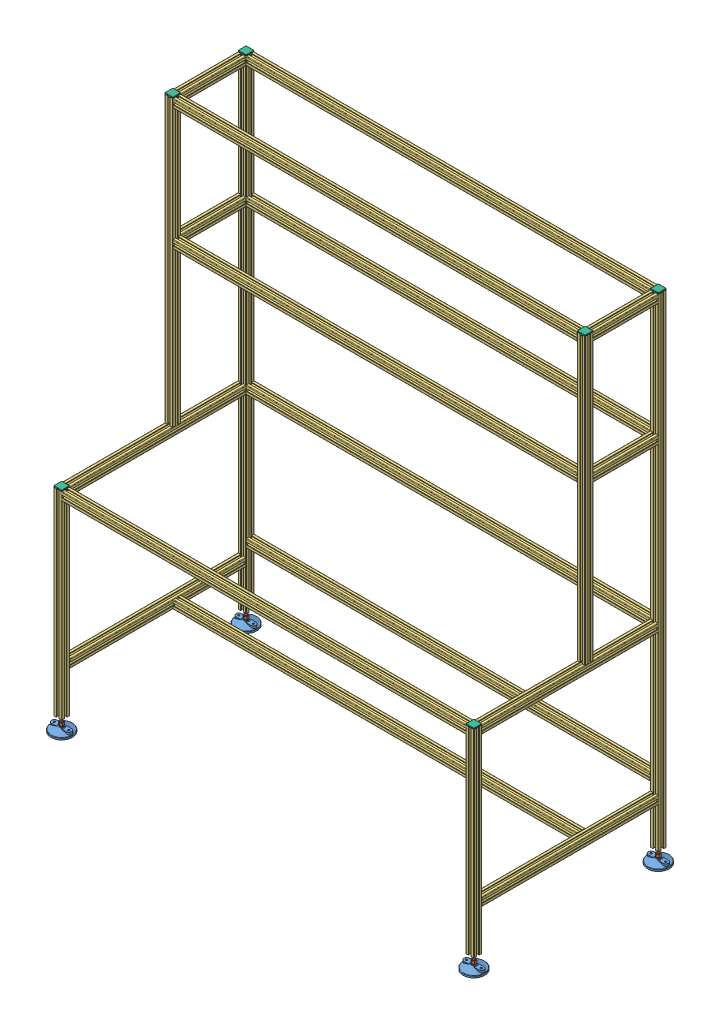
SolidWorks assembly AL-4 Рабочий стол большой с двумя полками, configuration По умолчанию. Lengths in mm.
Overall size (1599 1834.2 759).
75 component instances, 6 part files, 66 mates.
Components (placement in the parent):
- AL-340.010BA.01 Опора D80 с противоскользящей вставкой-8: AL-340.010BA.01 Опора D80 с противоскользящей вставкой [Default] x (0 0 1) z (1 0 0) size (79 18 79)
- AL-1Y12.A42A.01 Шпилька к опоре М8х80-1: AL-1Y12.A42A.01 Шпилька к опоре М8х80 [Default] x (0.999247 0 0.038788) z (0.038788 0 -0.999247) size (15 105.5 18.13)
- AL-4-PS-3030.001 Профиль-2: AL-4-PS-3030.001 Профиль [Default] at (0 1765 255) size (30 30 240)
- AL-4-PS-3030.001 Профиль-6: AL-4-PS-3030.001 Профиль [Default] at (-1520 1765 255) size (30 30 240)
- AL-4-PS-3030.001 Профиль-30: AL-4-PS-3030.001 Профиль [-01] at (0 715 665) x (0 1 0) z (0 0 1) size (30 30 650)
- AL-4-PS-3030.001 Профиль-31: AL-4-PS-3030.001 Профиль [-01] at (-1520 715 665) x (0 1 0) z (0 0 1) size (30 30 650)
- AL-4-PS-3030.001 Профиль-32: AL-4-PS-3030.001 Профиль [-01] at (0 165 665) size (30 30 650)
- AL-4-PS-3030.001 Профиль-33: AL-4-PS-3030.001 Профиль [-01] at (-1520 165 665) size (30 30 650)
- AL-4-PS-3030.001 Профиль-34: AL-4-PS-3030.001 Профиль [-02] at (0 0 680) x (1 0 0) z (0 -1 0) size (30 30 730)
- AL-4-PS-3030.001 Профиль-36: AL-4-PS-3030.001 Профиль [-03] at (0 730 270) x (0 0 1) z (0 -1 0) size (30 30 1050)
- AL-4-PS-3030.001 Профиль-35: AL-4-PS-3030.001 Профиль [-02] at (-1520 0 680) x (1 0 0) z (0 -1 0) size (30 30 730)
- AL-4-PS-3030.001 Профиль-38: AL-4-PS-3030.001 Профиль [-04] at (-1505 1765 270) x (0 0 1) z (-1 0 0) size (30 30 1490)
- AL-4-PS-3030.001 Профиль-40: AL-4-PS-3030.001 Профиль [-04] at (-1505 715 680) x (0 0 1) z (-1 0 0) size (30 30 1490)
- AL-4-PS-3030.001 Профиль-41: AL-4-PS-3030.001 Профиль [-04] at (-1505 715 0) x (0 0 1) z (-1 0 0) size (30 30 1490)
- AL-4-PS-3030.001 Профиль-42: AL-4-PS-3030.001 Профиль [-04] at (-1505 225 0) x (0 0 1) z (-1 0 0) size (30 30 1490)
- AL-4-PS-3030.001 Профиль-43: AL-4-PS-3030.001 Профиль [-04] at (-1505 1765 0) x (0 0 1) z (-1 0 0) size (30 30 1490)
- AL-4-PS-3030.001 Профиль-45: AL-4-PS-3030.001 Профиль [-04] at (-1505 165 270) x (0 0 1) z (-1 0 0) size (30 30 1490)
- AL-4-PS-3030.001 Профиль-46: AL-4-PS-3030.001 Профиль [-05] x (1 0 0) z (0 -1 0) size (30 30 1780)
- AL-4-PS-3030.001 Профиль-47: AL-4-PS-3030.001 Профиль [-05] at (-1520 0 0) x (1 0 0) z (0 -1 0) size (30 30 1780)
- AL-340.010BA.01 Опора D80 с противоскользящей вставкой-9: AL-340.010BA.01 Опора D80 с противоскользящей вставкой [Default] at (-1520 0 0) x (0 0 1) z (1 0 0) size (79 18 79)
- AL-340.010BA.01 Опора D80 с противоскользящей вставкой-10: AL-340.010BA.01 Опора D80 с противоскользящей вставкой [Default] at (0 0 680) x (0 0 1) z (1 0 0) size (79 18 79)
- AL-340.010BA.01 Опора D80 с противоскользящей вставкой-11: AL-340.010BA.01 Опора D80 с противоскользящей вставкой [Default] at (-1520 0 680) x (0 0 1) z (1 0 0) size (79 18 79)
- AL-1Y12.A42A.01 Шпилька к опоре М8х80-2: AL-1Y12.A42A.01 Шпилька к опоре М8х80 [Default] at (-1520 0 0) x (0.999247 0 0.038788) z (0.038788 0 -0.999247) size (15 105.5 18.13)
- AL-1Y12.A42A.01 Шпилька к опоре М8х80-3: AL-1Y12.A42A.01 Шпилька к опоре М8х80 [Default] at (0 0 680) x (0.999247 0 0.038788) z (0.038788 0 -0.999247) size (15 105.5 18.13)
- AL-1Y12.A42A.01 Шпилька к опоре М8х80-4: AL-1Y12.A42A.01 Шпилька к опоре М8х80 [Default] at (-1520 0 680) x (0.999247 0 0.038788) z (0.038788 0 -0.999247) size (15 105.5 18.13)
- AL-4-PS-3030.001 Профиль-37: AL-4-PS-3030.001 Профиль [-03] at (-1520 730 270) x (0 0 1) z (0 -1 0) size (30 30 1050)
- AL-4-PS-3030.001 Профиль-44: AL-4-PS-3030.001 Профиль [-04] at (-1505 1315 0) x (0 0 1) z (-1 0 0) size (30 30 1490)
- AL-4-PS-3030.001 Профиль-27: AL-4-PS-3030.001 Профиль [Default] at (-1520 1315 255) size (30 30 240)
- AL-4-PS-3030.001 Профиль-39: AL-4-PS-3030.001 Профиль [-04] at (-1505 1315 270) x (0 0 1) z (-1 0 0) size (30 30 1490)
- AL-4-PS-3030.001 Профиль-29: AL-4-PS-3030.001 Профиль [Default] at (0 1315 255) size (30 30 240)
- hex nut gradec_din-1: hex nut gradec_din [Hexagon Nut ISO 4034 - M8 - N] at (0 -7.9 0) x (0.999967 0 0.008076) z (0 -1 0) size (13 15.01 7.9)
- hex nut gradec_din-2: hex nut gradec_din [Hexagon Nut ISO 4034 - M8 - N] at (-1520 -7.9 0) x (0.999967 0 0.008076) z (0 -1 0) size (13 15.01 7.9)
- hex nut gradec_din-3: hex nut gradec_din [Hexagon Nut ISO 4034 - M8 - N] at (0 -7.9 680) x (0.999967 0 0.008076) z (0 -1 0) size (13 15.01 7.9)
- hex nut gradec_din-4: hex nut gradec_din [Hexagon Nut ISO 4034 - M8 - N] at (-1520 -7.9 680) x (0.999967 0 0.008076) z (0 -1 0) size (13 15.01 7.9)
- socket button head screw_iso2-1: socket button head screw_iso2 [ISO 7380 - M8 x 25 - 25S] at (0 165 8.4) x (0 0 1) z (-1 0 0) size (29.4 14 14)
- socket button head screw_iso2-2: socket button head screw_iso2 [ISO 7380 - M8 x 25 - 25S] at (-8.4 225 0) x (-1 0 0) z (0 -0.924225 -0.381849) size (29.4 14 14)
- socket button head screw_iso2-3: socket button head screw_iso2 [ISO 7380 - M8 x 25 - 25S] at (-8.4 715 0) x (-1 0 0) z (0 -0.924225 -0.381849) size (29.4 14 14)
- socket button head screw_iso2-4: socket button head screw_iso2 [ISO 7380 - M8 x 25 - 25S] at (0 715 8.4) x (0 0 1) z (-0.432301 -0.901729 0) size (29.4 14 14)
- socket button head screw_iso2-5: socket button head screw_iso2 [ISO 7380 - M8 x 25 - 25S] at (-8.4 165 270) x (-1 0 0) z (0 -0.924225 -0.381849) size (29.4 14 14)
- socket button head screw_iso2-6: socket button head screw_iso2 [ISO 7380 - M8 x 25 - 25S] at (0 165 671.6) x (0 0 -1) z (0.381849 -0.924225 0) size (29.4 14 14)
- socket button head screw_iso2-7: socket button head screw_iso2 [ISO 7380 - M8 x 25 - 25S] at (0 715 671.6) x (0 0 -1) z (0.923728 0.383049 0) size (29.4 14 14)
- socket button head screw_iso2-9: socket button head screw_iso2 [ISO 7380 - M8 x 25 - 25S] at (-8.4 715 680) x (-1 0 0) z (0 -0.11281 -0.993617) size (29.4 14 14)
- socket button head screw_iso2-10: socket button head screw_iso2 [ISO 7380 - M8 x 25 - 25S] at (0 723.4 270) x (0 1 0) z (-0.924225 0 -0.381849) size (29.4 14 14)
- socket button head screw_iso2-11: socket button head screw_iso2 [ISO 7380 - M8 x 25 - 25S] at (-8.4 1765 0) x (-1 0 0) z (0 0 -1) size (29.4 14 14)
- socket button head screw_iso2-12: socket button head screw_iso2 [ISO 7380 - M8 x 25 - 25S] at (0 1765 8.4) x (0 0 1) z (-1 0 0) size (29.4 14 14)
- socket button head screw_iso2-13: socket button head screw_iso2 [ISO 7380 - M8 x 25 - 25S] at (-8.4 1315 0) x (-1 0 0) z (0 0 -1) size (29.4 14 14)
- socket button head screw_iso2-14: socket button head screw_iso2 [ISO 7380 - M8 x 25 - 25S] at (0 1315 8.4) x (0 0 1) z (-1 0 0) size (29.4 14 14)
- socket button head screw_iso2-17: socket button head screw_iso2 [ISO 7380 - M8 x 25 - 25S] at (-8.4 1765 270) x (-1 0 0) z (0 0 -1) size (29.4 14 14)
- socket button head screw_iso2-18: socket button head screw_iso2 [ISO 7380 - M8 x 25 - 25S] at (0 1765 261.6) x (0 0 -1) z (1 0 0) size (29.4 14 14)
- socket button head screw_iso2-19: socket button head screw_iso2 [ISO 7380 - M8 x 25 - 25S] at (-8.4 1315 270) x (-1 0 0) z (0 0 -1) size (29.4 14 14)
- socket button head screw_iso2-20: socket button head screw_iso2 [ISO 7380 - M8 x 25 - 25S] at (0 1315 261.6) x (0 0 -1) z (1 0 0) size (29.4 14 14)
- hex nut gradec_din-5: hex nut gradec_din [Hexagon Nut ISO 4034 - M8 - N] at (-1520 0 0) x (-0.999967 0 0.008076) z (0 1 0) size (13 15.01 7.9)
- socket button head screw_iso2-21: socket button head screw_iso2 [ISO 7380 - M8 x 25 - 25S] at (-1520 1315 8.4) x (0 0 1) z (-1 0 0) size (29.4 14 14)
- socket button head screw_iso2-22: socket button head screw_iso2 [ISO 7380 - M8 x 25 - 25S] at (-1511.6 1315 0) size (29.4 14 14)
- socket button head screw_iso2-23: socket button head screw_iso2 [ISO 7380 - M8 x 25 - 25S] at (-1520 1765 8.4) x (0 0 1) z (-1 0 0) size (29.4 14 14)
- socket button head screw_iso2-24: socket button head screw_iso2 [ISO 7380 - M8 x 25 - 25S] at (-1511.6 1765 0) size (29.4 14 14)
- socket button head screw_iso2-25: socket button head screw_iso2 [ISO 7380 - M8 x 25 - 25S] at (-1520 723.4 270) x (0 1 0) z (-0.924225 0 0.381849) size (29.4 14 14)
- socket button head screw_iso2-26: socket button head screw_iso2 [ISO 7380 - M8 x 25 - 25S] at (-1511.6 715 680) x (1 0 0) z (0 0.11281 0.993617) size (29.4 14 14)
- socket button head screw_iso2-27: socket button head screw_iso2 [ISO 7380 - M8 x 25 - 25S] at (-1520 715 671.6) x (0 0 -1) z (0.923728 -0.383049 0) size (29.4 14 14)
- socket button head screw_iso2-28: socket button head screw_iso2 [ISO 7380 - M8 x 25 - 25S] at (-1520 165 671.6) x (0 0 -1) z (0.381849 0.924225 0) size (29.4 14 14)
- socket button head screw_iso2-29: socket button head screw_iso2 [ISO 7380 - M8 x 25 - 25S] at (-1511.6 165 270) x (1 0 0) z (0 0.924225 0.381849) size (29.4 14 14)
- socket button head screw_iso2-30: socket button head screw_iso2 [ISO 7380 - M8 x 25 - 25S] at (-1520 715 8.4) x (0 0 1) z (-0.432301 0.901729 0) size (29.4 14 14)
- socket button head screw_iso2-31: socket button head screw_iso2 [ISO 7380 - M8 x 25 - 25S] at (-1511.6 715 0) x (1 0 0) z (0 0.924225 0.381849) size (29.4 14 14)
- socket button head screw_iso2-32: socket button head screw_iso2 [ISO 7380 - M8 x 25 - 25S] at (-1511.6 225 0) x (1 0 0) z (0 0.924225 0.381849) size (29.4 14 14)
- socket button head screw_iso2-33: socket button head screw_iso2 [ISO 7380 - M8 x 25 - 25S] at (-1520 165 8.4) x (0 0 1) z (-1 0 0) size (29.4 14 14)
- socket button head screw_iso2-34: socket button head screw_iso2 [ISO 7380 - M8 x 25 - 25S] at (-1511.6 1765 270) size (29.4 14 14)
- socket button head screw_iso2-35: socket button head screw_iso2 [ISO 7380 - M8 x 25 - 25S] at (-1520 1765 261.6) x (0 0 -1) z (1 0 0) size (29.4 14 14)
- socket button head screw_iso2-36: socket button head screw_iso2 [ISO 7380 - M8 x 25 - 25S] at (-1511.6 1315 270) size (29.4 14 14)
- socket button head screw_iso2-37: socket button head screw_iso2 [ISO 7380 - M8 x 25 - 25S] at (-1520 1315 261.6) x (0 0 -1) z (1 0 0) size (29.4 14 14)
- AL-375.0200A.01 Заглушка торцевая 30х30-34: AL-375.0200A.01 Заглушка торцевая 30х30 [По умолчанию] at (-15 1784.2 -15) x (1 0 0) z (0 -1 0) size (30 30 9.2)
- AL-375.0200A.01 Заглушка торцевая 30х30-35: AL-375.0200A.01 Заглушка торцевая 30х30 [По умолчанию] at (-15 734.2 665) x (1 0 0) z (0 -1 0) size (30 30 9.2)
- AL-375.0200A.01 Заглушка торцевая 30х30-36: AL-375.0200A.01 Заглушка торцевая 30х30 [По умолчанию] at (15 1784.2 285) x (-1 0 0) z (0 -1 0) size (30 30 9.2)
- AL-375.0200A.01 Заглушка торцевая 30х30-37: AL-375.0200A.01 Заглушка торцевая 30х30 [По умолчанию] at (-1535 734.2 665) x (1 0 0) z (0 -1 0) size (30 30 9.2)
- AL-375.0200A.01 Заглушка торцевая 30х30-38: AL-375.0200A.01 Заглушка торцевая 30х30 [По умолчанию] at (-1505 1784.2 285) x (-1 0 0) z (0 -1 0) size (30 30 9.2)
- AL-375.0200A.01 Заглушка торцевая 30х30-39: AL-375.0200A.01 Заглушка торцевая 30х30 [По умолчанию] at (-1535 1784.2 -15) x (1 0 0) z (0 -1 0) size (30 30 9.2)
Mates (geometry in assembly coordinates):
- Совпадение1: coincident aligned: plane of AL-3-PS-3030.001 Профиль-22 through (0 0 0) normal (0 0 1)
- Совпадение2: coincident anti-aligned: plane of AL-3-PS-3030.001 Профиль-22 through (0 0 0) normal (0 -1 0)
- Совпадение3: coincident aligned: plane of AL-3-PS-3030.001 Профиль-22 through (0 0 0) normal (1 0 0)
- Совпадение4: coincident aligned: plane of AL-3-PS-3030.001 Профиль-22 through (15 1780 13) normal (1 0 0); plane of AL-3-PS-3030.001 Профиль-2 through (15 1778 15) normal (1 0 0)
- Совпадение5: coincident anti-aligned: plane of AL-3-PS-3030.001 Профиль-22 through (4.75 1780 15) normal (0 0 1); plane of AL-3-PS-3030.001 Профиль-2 through (-8.05 1752.4 15) normal (0 0 -1)
- Совпадение6: coincident aligned: plane of AL-3-PS-3030.001 Профиль-22 through (-8.05 1780 -12.6) normal (0 1 0); plane of AL-3-PS-3030.001 Профиль-2 through (-4.75 1780 15) normal (0 1 0)
- Совпадение7: coincident aligned: plane of AL-3-PS-3030.001 Профиль-22 through (15 1780 13) normal (1 0 0); plane of AL-3-PS-3030.001 Профиль-11 through (15 730 667) normal (1 0 0)
- Совпадение8: coincident aligned: plane of AL-3-PS-3030.001 Профиль-22 through (-8.05 0 -12.6) normal (0 -1 0); plane of AL-3-PS-3030.001 Профиль-11 through (-8.05 0 667.4) normal (0 -1 0)
- Совпадение11: coincident anti-aligned: plane of AL-3-PS-3030.001 Профиль-11 through (4.75 730 665) normal (0 0 -1); plane of AL-3-PS-3030.001 Профиль-7 through (12.6 706.95 665) normal (0 0 1)
- Совпадение12: coincident anti-aligned: plane of AL-3-PS-3030.001 Профиль-22 through (4.75 1780 15) normal (0 0 1); plane of AL-3-PS-3030.001 Профиль-7 through (12.6 706.95 15) normal (0 0 -1)
- Расстояние1: distance = 150 mm aligned: plane of AL-3-PS-3030.001 Профиль-9 through (4.75 150 15) normal (0 -1 0); plane of AL-3-PS-3030.001 Профиль-11 through (-8.05 0 667.4) normal (0 -1 0)
- Совпадение15: coincident anti-aligned: plane of AL-3-PS-3030.001 Профиль-11 through (4.75 730 665) normal (0 0 -1); plane of AL-3-PS-3030.001 Профиль-9 through (-8.05 152.4 665) normal (0 0 1)
- Совпадение16: coincident aligned: plane of AL-3-PS-3030.001 Профиль-11 through (-8.05 730 667.4) normal (0 1 0); plane of AL-4-PS-3030.001 Профиль-40 through (-15 730 684.75) normal (0 1 0)
- Совпадение17: coincident aligned: plane of AL-3-PS-3030.001 Профиль-11 through (-4.75 730 695) normal (0 0 1); plane of AL-4-PS-3030.001 Профиль-40 through (-15 728 695) normal (0 0 1)
- Совпадение18: coincident anti-aligned: plane of AL-3-PS-3030.001 Профиль-11 through (-15 730 693) normal (-1 0 0); plane of AL-4-PS-3030.001 Профиль-40 through (-15 702.4 671.95) normal (1 0 0)
- Совпадение19: coincident aligned: plane of AL-4-PS-3030.001 Профиль-40 through (-15 730 684.75) normal (0 1 0); plane of AL-4-PS-3030.001 Профиль-41 through (-15 730 4.75) normal (0 1 0)
- Совпадение20: coincident aligned: plane of AL-4-PS-3030.001 Профиль-47 through (-1515.25 1780 -15) normal (0 0 -1); plane of AL-4-PS-3030.001 Профиль-41 through (-15 728 -15) normal (0 0 -1)
- Совпадение21: coincident aligned: plane of AL-4-PS-3030.001 Профиль-40 through (-1505 702.4 671.95) normal (-1 0 0); plane of AL-4-PS-3030.001 Профиль-41 through (-1505 702.4 -8.05) normal (-1 0 0)
- Совпадение22: coincident aligned: plane of AL-3-PS-3030.001 Профиль-9 through (4.75 180 15) normal (0 1 0); plane of AL-4-PS-3030.001 Профиль-45 through (-15 180 274.75) normal (0 1 0)
- Совпадение23: coincident anti-aligned: plane of AL-3-PS-3030.001 Профиль-9 through (-15 152 15) normal (-1 0 0); plane of AL-4-PS-3030.001 Профиль-45 through (-15 152.4 261.95) normal (1 0 0)
- Расстояние2: distance = 240 mm anti-aligned: plane of AL-3-PS-3030.001 Профиль-21 through (-15 178 255) normal (0 0 -1); plane of AL-3-PS-3030.001 Профиль-22 through (-4.75 1780 15) normal (0 0 1)
- Совпадение26: coincident anti-aligned: plane of AL-3-PS-3030.001 Профиль-2 through (-15 1778 15) normal (-1 0 0); plane of AL-4-PS-3030.001 Профиль-38 through (-15 1752.4 261.95) normal (1 0 0)
- Совпадение27: coincident aligned: plane of AL-3-PS-3030.001 Профиль-2 through (-4.75 1780 15) normal (0 1 0); plane of AL-4-PS-3030.001 Профиль-38 through (-15 1780 274.75) normal (0 1 0)
- Концентричный2: concentric anti-aligned: cylinder of AL-1Y12.A42A.01 Шпилька к опоре М8х80-1 through (0 -18 0) axis (0 1 0) radius 4; cylinder of AL-340.010BA.01 Опора D80 с противоскользящей вставкой-8 through (0 0 0) axis (0 -1 0) radius 39.5
- Концентричный272: concentric anti-aligned: cylinder of AL-3-PS-3030.001 Профиль-22 through (0 1780 0) axis (0 -1 0) radius 3.65; cylinder of AL-1Y12.A42A.01 Шпилька к опоре М8х80-1 through (0 -18 0) axis (0 1 0) radius 4
- Совпадение563: coincident aligned: plane of AL-3-PS-3030.001 Профиль-7 through (-13 730 15) normal (0 1 0); plane of AL-3-PS-3030.001 Профиль-11 through (-8.05 730 667.4) normal (0 1 0)
- Совпадение564: coincident aligned: plane of AL-3-PS-3030.001 Профиль-7 through (15 719.75 15) normal (1 0 0); plane of AL-3-PS-3030.001 Профиль-11 through (15 730 667) normal (1 0 0)
- Совпадение565: coincident aligned: plane of AL-3-PS-3030.001 Профиль-7 through (15 719.75 15) normal (1 0 0); plane of AL-3-PS-3030.001 Профиль-9 through (15 178 15) normal (1 0 0)
- Расстояние4: distance = 300 mm anti-aligned: plane of AL-3-PS-3030.001 Профиль-16 through (-15 1778 285) normal (0 0 1); plane of AL-3-PS-3030.001 Профиль-20 through (-15 1778 -15) normal (0 0 -1)
- Совпадение567: coincident anti-aligned: plane of AL-3-PS-3030.001 Профиль-2 through (-8.05 1752.4 255) normal (0 0 1); plane of AL-3-PS-3030.001 Профиль-24 through (-13 1780 255) normal (0 0 -1)
- Совпадение568: coincident anti-aligned: plane of AL-3-PS-3030.001 Профиль-24 through (-15 1780 274.75) normal (-1 0 0); plane of AL-4-PS-3030.001 Профиль-38 through (-15 1752.4 261.95) normal (1 0 0)
- Совпадение569: coincident aligned: plane of AL-3-PS-3030.001 Профиль-24 through (12.6 1780 261.95) normal (0 1 0); plane of AL-4-PS-3030.001 Профиль-38 through (-15 1780 274.75) normal (0 1 0)
- Концентричный273: concentric anti-aligned: cylinder of AL-1Y12.A42A.01 Шпилька к опоре М8х80-1 through (0 -18 0) axis (0 1 0) radius 4; cylinder of hex nut gradec_din-1 through (0 0 0) axis (0 -1 0) radius 3.4
- Совпадение570: coincident anti-aligned: plane of AL-4-PS-3030.001 Профиль-46 through (-8.05 0 -12.6) normal (0 -1 0); plane of hex nut gradec_din-1 through (-12.9996 0 -0.105) normal (0 1 0)
- Совпадение571: coincident anti-aligned: plane of AL-4-PS-3030.001 Профиль-46 through (-12.8 1780 -8.05) normal (1 0 0); plane of socket button head screw_iso-2 through (-12.8 226.5274 -3.6969) normal (-1 0 0)
- Концентричный274: concentric anti-aligned: cylinder of AL-4-PS-3030.001 Профиль-42 through (-15 225 0) axis (-1 0 0) radius 3.65; circle of socket button head screw_iso-2
- Совпадение572: coincident anti-aligned: plane of AL-4-PS-3030.001 Профиль-46 through (4.65 1780 12.8) normal (0 0 -1); plane of socket button head screw_iso-1 through (0 169 12.8) normal (0 0 1)
- Концентричный275: concentric anti-aligned: cylinder of AL-4-PS-3030.001 Профиль-32 through (0 165 15) axis (0 0 1) radius 3.65; cylinder of socket button head screw_iso-1 through (0 165 8.4) axis (0 0 -1) radius 4
- Концентричный276: concentric anti-aligned: cylinder of AL-4-PS-3030.001 Профиль-41 through (-15 715 0) axis (-1 0 0) radius 3.65; circle of socket button head screw_iso-3
- Совпадение578: coincident anti-aligned: plane of AL-4-PS-3030.001 Профиль-46 through (-12.8 1780 8.05) normal (1 0 0); plane of socket button head screw_iso-3 through (-12.8 716.5274 -3.6969) normal (-1 0 0)
- Совпадение579: coincident anti-aligned: plane of AL-4-PS-3030.001 Профиль-46 through (4.65 1780 12.8) normal (0 0 -1); plane of socket button head screw_iso-4 through (-3.6069 716.7292 12.8) normal (0 0 1)
- Концентричный277: concentric anti-aligned: cylinder of AL-4-PS-3030.001 Профиль-30 through (0 715 15) axis (0 0 1) radius 3.65; circle of socket button head screw_iso-4
- Совпадение580: coincident anti-aligned: plane of AL-4-PS-3030.001 Профиль-32 through (-12.8 156.95 15) normal (1 0 0); plane of socket button head screw_iso-5 through (-12.8 166.5274 266.3031) normal (-1 0 0)
- Концентричный278: concentric anti-aligned: cylinder of AL-4-PS-3030.001 Профиль-45 through (-15 165 270) axis (-1 0 0) radius 3.65; circle of socket button head screw_iso-5
- Совпадение581: coincident anti-aligned: plane of AL-4-PS-3030.001 Профиль-34 through (-4.65 730 667.2) normal (0 0 1); plane of socket button head screw_iso-6 through (3.6969 166.5274 667.2) normal (0 0 -1)
- Концентричный279: concentric aligned: cylinder of AL-4-PS-3030.001 Профиль-32 through (0 165 15) axis (0 0 1) radius 3.65; circle of socket button head screw_iso-6
- Совпадение582: coincident anti-aligned: plane of AL-4-PS-3030.001 Профиль-34 through (-4.65 730 667.2) normal (0 0 1); plane of socket button head screw_iso-7 through (-1.5322 718.6949 667.2) normal (0 0 -1)
- Концентричный280: concentric aligned: circle of AL-4-PS-3030.001 Профиль-30; circle of socket button head screw_iso-7
- Совпадение583: coincident anti-aligned: plane of AL-4-PS-3030.001 Профиль-34 through (-12.8 730 688.05) normal (1 0 0); plane of socket button head screw_iso-9 through (-12.8 718.9745 679.5488) normal (-1 0 0)
- Концентричный281: concentric anti-aligned: cylinder of AL-4-PS-3030.001 Профиль-40 through (-15 715 680) axis (-1 0 0) radius 3.65; circle of socket button head screw_iso-9
- Совпадение584: coincident anti-aligned: plane of AL-4-PS-3030.001 Профиль-30 through (8.05 727.8 15) normal (0 -1 0); plane of socket button head screw_iso-10 through (1.5274 727.8 266.3031) normal (0 1 0)
- Концентричный282: concentric aligned: cylinder of AL-4-PS-3030.001 Профиль-36 through (0 1780 270) axis (0 -1 0) radius 3.65; circle of socket button head screw_iso-10
- Совпадение585: coincident anti-aligned: plane of AL-4-PS-3030.001 Профиль-46 through (-4.65 1780 12.8) normal (0 0 -1); plane of socket button head screw_iso-12 through (0 1769 12.8) normal (0 0 1)
- Концентричный283: concentric anti-aligned: cylinder of AL-4-PS-3030.001 Профиль-2 through (0 1765 15) axis (0 0 1) radius 3.65; circle of socket button head screw_iso-12
- Совпадение586: coincident anti-aligned: plane of AL-4-PS-3030.001 Профиль-46 through (-12.8 1780 -8.05) normal (1 0 0); plane of socket button head screw_iso-11 through (-12.8 1769 0) normal (-1 0 0)
- Концентричный284: concentric anti-aligned: cylinder of AL-4-PS-3030.001 Профиль-43 through (-15 1765 0) axis (-1 0 0) radius 3.65; circle of socket button head screw_iso-11
- Совпадение587: coincident anti-aligned: plane of AL-4-PS-3030.001 Профиль-46 through (-4.65 1780 12.8) normal (0 0 -1); plane of socket button head screw_iso-14 through (0 1319 12.8) normal (0 0 1)
- Концентричный285: concentric anti-aligned: cylinder of AL-4-PS-3030.001 Профиль-29 through (0 1315 15) axis (0 0 1) radius 3.65; circle of socket button head screw_iso-14
- Совпадение588: coincident anti-aligned: plane of AL-4-PS-3030.001 Профиль-46 through (-12.8 1780 -8.05) normal (1 0 0); plane of socket button head screw_iso-13 through (-12.8 1319 0) normal (-1 0 0)
- Концентричный286: concentric anti-aligned: cylinder of AL-4-PS-3030.001 Профиль-44 through (-15 1315 0) axis (-1 0 0) radius 3.65; circle of socket button head screw_iso-13
- Совпадение589: coincident anti-aligned: plane of AL-4-PS-3030.001 Профиль-46 through (-8.05 1780 -12.6) normal (0 1 0); plane of AL-375.0200A.01 Заглушка торцевая 30х30-34 through (3.6986 1780 15) normal (0 -1 0)
- Совпадение590: coincident aligned: plane of AL-4-PS-3030.001 Профиль-46 through (15 1780 -13) normal (1 0 0); plane of AL-375.0200A.01 Заглушка торцевая 30х30-34 through (15 1784.2 -15) normal (1 0 0)
- Совпадение591: coincident aligned: plane of AL-4-PS-3030.001 Профиль-46 through (4.75 1780 -15) normal (0 0 -1); plane of AL-375.0200A.01 Заглушка торцевая 30х30-34 through (-15 1784.2 -15) normal (0 0 -1)
- Совпадение592: coincident anti-aligned: plane of AL-4-PS-3030.001 Профиль-34 through (-8.05 730 667.4) normal (0 1 0); plane of AL-375.0200A.01 Заглушка торцевая 30х30-35 through (3.6986 730 695) normal (0 -1 0)
- Совпадение593: coincident aligned: plane of AL-4-PS-3030.001 Профиль-34 through (15 730 667) normal (1 0 0); plane of AL-375.0200A.01 Заглушка торцевая 30х30-35 through (15 734.2 665) normal (1 0 0)
- Совпадение594: coincident aligned: plane of AL-4-PS-3030.001 Профиль-34 through (4.75 730 695) normal (0 0 1); plane of AL-375.0200A.01 Заглушка торцевая 30х30-35 through (-15 734.2 695) normal (0 0 1)
